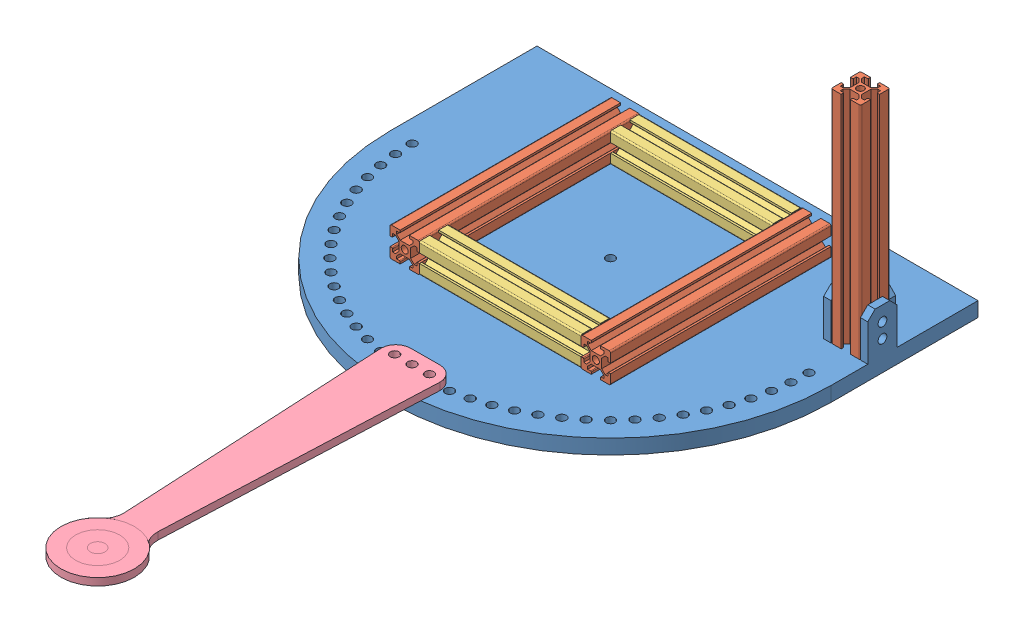
SolidWorks assembly Assem1, configuration Default. Lengths in mm.
Overall size (300 160 475.13).
7 component instances, 4 part files, 21 mates.
Components (placement in the parent):
- Plate.MISSION2-1: Plate.MISSION2 [Default] at (120.2292 84.857 236.0475) size (300 40 250)
- Alu150mlxx2-1: Alu150mlxx2 [Default] at (185.2292 104.857 161.0475) x (0 1 0) z (1 0 0) size (20 150 20)
- Alu150mlxx2-2: Alu150mlxx2 [Default] at (55.2292 104.857 161.0475) x (0 1 0) z (1 0 0) size (20 150 20)
- Alu110mlxx2-1: Alu110mlxx2 [Default] at (175.2292 104.857 301.0475) x (0 1 0) z (0 0 1) size (20 110 20)
- Alu110mlxx2-2: Alu110mlxx2 [Default] at (175.2292 104.857 171.0475) x (0 1 0) z (0 0 1) size (20 110 20)
- Alu150mlxx2-3: Alu150mlxx2 [Default] at (255.2292 94.857 201.0475) size (20 150 20)
- Target (1)-1: Target (1) [Default] at (121.3399 94.857 586.0446) x (-0.999987 0 0.005166) z (-0.005166 0 -0.999987) size (50 5 249)
Mates (geometry in assembly coordinates):
- Coincident4: coincident anti-aligned: plane of Alu150mlxx2-1 through (175.2292 104.857 311.0475) normal (-1 0 0); plane of Alu110mlxx2-1 through (175.2292 104.857 301.0475) normal (1 0 0)
- Coincident5: coincident anti-aligned: plane of Alu150mlxx2-1 through (175.2292 104.857 311.0475) normal (-1 0 0); plane of Alu110mlxx2-2 through (175.2292 104.857 171.0475) normal (1 0 0)
- Coincident6: coincident aligned: plane of Alu150mlxx2-1 through (185.2292 104.857 161.0475) normal (0 0 -1); plane of Alu110mlxx2-2 through (65.2292 104.857 161.0475) normal (0 0 -1)
- Coincident7: coincident aligned: plane of Alu150mlxx2-2 through (55.2292 104.857 161.0475) normal (0 0 -1); plane of Alu110mlxx2-2 through (65.2292 104.857 161.0475) normal (0 0 -1)
- Coincident8: coincident anti-aligned: plane of Alu150mlxx2-2 through (65.2292 104.857 311.0475) normal (1 0 0); plane of Alu110mlxx2-2 through (65.2292 104.857 171.0475) normal (-1 0 0)
- Coincident9: coincident anti-aligned: plane of Alu150mlxx2-2 through (65.2292 104.857 311.0475) normal (1 0 0); plane of Alu110mlxx2-1 through (65.2292 104.857 301.0475) normal (-1 0 0)
- Coincident10: coincident aligned: plane of Alu150mlxx2-2 through (55.2292 104.857 311.0475) normal (0 0 1); plane of Alu110mlxx2-1 through (65.2292 104.857 311.0475) normal (0 0 1)
- Coincident11: coincident aligned: plane of Alu150mlxx2-2 through (55.2292 114.857 311.0475) normal (0 1 0); plane of Alu110mlxx2-2 through (65.2292 114.857 171.0475) normal (0 1 0)
- Coincident12: coincident aligned: plane of Alu150mlxx2-1 through (185.2292 114.857 311.0475) normal (0 1 0); plane of Alu110mlxx2-2 through (65.2292 114.857 171.0475) normal (0 1 0)
- Coincident13: coincident aligned: plane of Alu150mlxx2-1 through (185.2292 114.857 311.0475) normal (0 1 0); plane of Alu110mlxx2-1 through (65.2292 114.857 301.0475) normal (0 1 0)
- Coincident14: coincident aligned: plane of Alu150mlxx2-2 through (55.2292 114.857 311.0475) normal (0 1 0); plane of Alu110mlxx2-1 through (65.2292 114.857 301.0475) normal (0 1 0)
- Distance1: distance = 75 mm: point of Plate.MISSION2-1; plane of Alu110mlxx2-1 through (65.2292 104.857 311.0475) normal (0 0 1)
- Distance2: distance = 75 mm: plane of Alu150mlxx2-2 through (45.2292 104.857 311.0475) normal (-1 0 0); unknown of Plate.MISSION2-1
- Coincident19: coincident anti-aligned: plane of Plate.MISSION2-1 through (120.2292 94.857 236.0475) normal (0 1 0); plane of Alu150mlxx2-1 through (185.2292 94.857 311.0475) normal (0 -1 0)
- Parallel1: parallel anti-aligned: plane of Plate.MISSION2-1 through (240.2292 84.857 236.0475) normal (-1 0 0); plane of Alu150mlxx2-1 through (195.2292 104.857 311.0475) normal (1 0 0)
- Coincident20: coincident anti-aligned: plane of Plate.MISSION2-1 through (246.2292 124.857 191.0475) normal (0 0 1); plane of Alu150mlxx2-3 through (255.2292 244.857 191.0475) normal (0 0 -1)
- Coincident22: coincident anti-aligned: plane of Plate.MISSION2-1 through (120.2292 94.857 236.0475) normal (0 1 0); plane of Alu150mlxx2-3 through (255.2292 94.857 201.0475) normal (0 -1 0)
- Coincident23: coincident anti-aligned: plane of Plate.MISSION2-1 through (265.2292 84.857 236.0475) normal (-1 0 0); plane of Alu150mlxx2-3 through (265.2292 244.857 201.0475) normal (1 0 0)
- Concentric1: concentric: cylinder of Plate.MISSION2-1 through (120.2292 94.857 371.0475) axis (0 -1 0) radius 3; cylinder of Target (1)-1 through (120.2292 112.5446 371.0475) axis (0 -1 0) radius 3
- Concentric2: concentric: cylinder of Plate.MISSION2-1 through (120.2292 94.857 371.0475) axis (0 -1 0) radius 3; cylinder of Target (1)-1 through (120.2292 99.8569 371.0475) axis (0 -1 0) radius 3
- Coincident25: coincident anti-aligned: plane of Plate.MISSION2-1 through (120.2292 94.857 236.0475) normal (0 1 0); plane of Target (1)-1 through (121.3399 94.857 586.0446) normal (0 -1 0)
